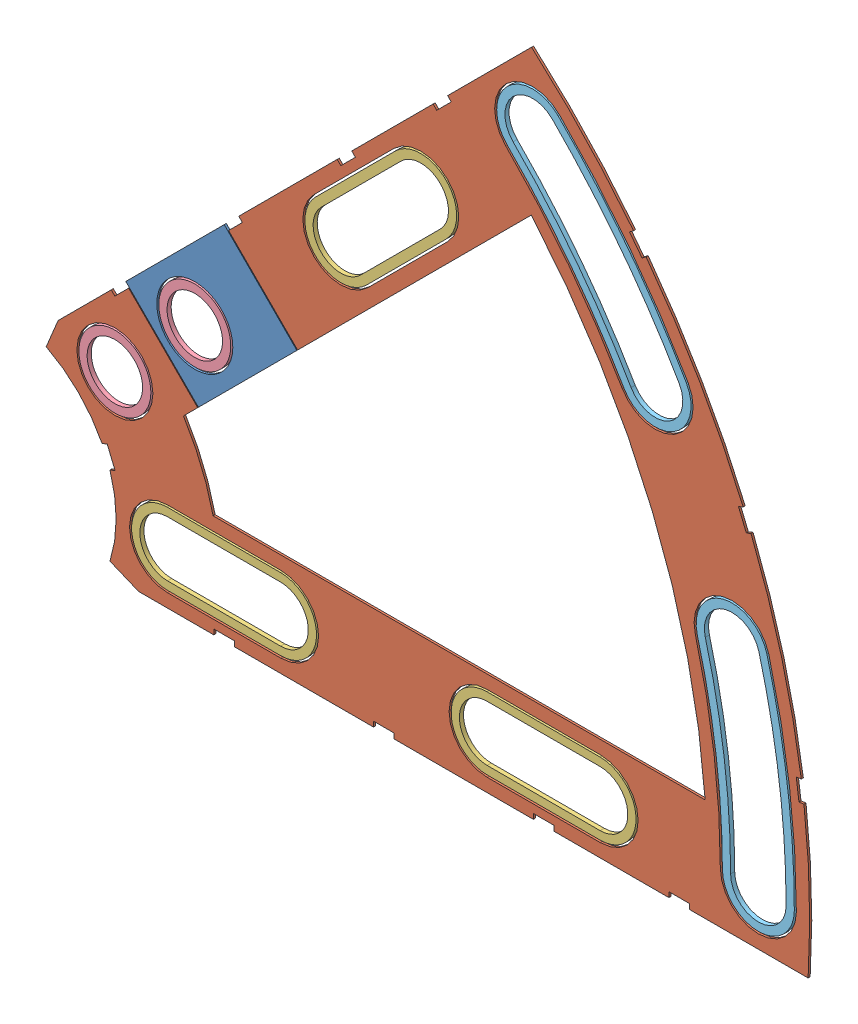
SolidWorks assembly Clover_2_Insul+Pass, configuration Default. Lengths in mm.
Overall size (94.37 82.54 0.51).
9 component instances, 5 part files, 22 mates.
Components (placement in the parent):
- Clover_2_Pass-1: Clover_2_Pass [Default] at (-7.6628 -2.4823 32.3476) size (21.15 21.15 0.25)
- Clover_2_Insul-1: Clover_2_Insul [Default] at (-7.6628 -2.4823 32.3476) size (94.37 82.54 0.25)
- Clover_Short_Washer-1: Clover_Short_Washer [Default] at (21.5472 -2.4823 32.6016) x (1 0 0) z (0 1 0) size (22.86 0.51 8.89)
- Clover_Short_Washer-2: Clover_Short_Washer [Default] at (61.0442 -2.4823 32.6016) x (1 0 0) z (0 1 0) size (22.86 0.51 8.89)
- Clover_Short_Washer-3: Clover_Short_Washer [Default] at (40.9204 46.1009 32.6016) x (0.707107 0.707107 0) z (-0.707107 0.707107 0) size (22.86 0.51 8.89)
- Round_Washer-1: Round_Washer [Default] at (8.0526 13.2332 32.6016) x (1 0 0) z (0 1 0) size (8.89 0.51 8.89)
- Round_Washer-2: Round_Washer [Default] at (17.9309 23.1115 32.6016) x (1 0 0) z (0 1 0) size (8.89 0.51 8.89)
- Clover_Outside_Washer-1: Clover_Outside_Washer [Default] at (-7.6628 -2.4823 32.0936) x (0.866025 0.5 0) z (0.5 -0.866025 0) size (12.14 0.51 33.54)
- Clover_Outside_Washer-2: Clover_Outside_Washer [Default] at (-7.6628 -2.4823 32.0936) x (1 0 0) z (0 -1 0) size (12.14 0.51 33.54)
Mates (geometry in assembly coordinates):
- Coincident1: coincident: plane of Clover_2_Pass-1 through (-7.6628 -2.4823 32.6016) normal (0 0 1); plane of Clover_2_Insul-1 through (-7.6628 -2.4823 32.6016) normal (0 0 1)
- Coincident3: coincident: plane of Clover_2_Pass-1 through (59.5487 73.7094 32.6016) normal (-0.707107 0.707107 0); plane of Clover_2_Insul-1 through (59.5487 73.7094 32.6016) normal (-0.707107 0.707107 0)
- Distance1: distance = 2.54 mm: plane of Clover_2_Pass-1 through (9.3997 23.5605 32.3476) normal (-0.707107 -0.707107 0); plane of Clover_2_Insul-1 through (7.6036 21.7644 32.3476) normal (0.707107 0.707107 0)
- Concentric1: concentric: circle of Clover_2_Insul-1; circle of Clover_Outside_Washer-1
- Concentric2: concentric: circle of Clover_2_Insul-1; circle of Clover_Outside_Washer-1
- Coincident4: coincident: plane of Clover_2_Insul-1 through (-7.6628 -2.4823 32.6016) normal (0 0 1); plane of Clover_Outside_Washer-1 through (33.5816 21.3302 32.6016) normal (0 0 1)
- Concentric3: concentric: circle of Clover_2_Insul-1; circle of Clover_Outside_Washer-2
- Concentric4: concentric: circle of Clover_2_Insul-1; circle of Clover_Outside_Washer-2
- Coincident5: coincident: plane of Clover_2_Insul-1 through (-7.6628 -2.4823 32.6016) normal (0 0 1); plane of Clover_Outside_Washer-2 through (39.9622 -2.4823 32.6016) normal (0 0 1)
- Concentric5: concentric: circle of Clover_2_Insul-1; circle of Clover_Short_Washer-2
- Concentric6: concentric: circle of Clover_2_Insul-1; circle of Clover_Short_Washer-2
- Coincident6: coincident: plane of Clover_2_Insul-1 through (-7.6628 -2.4823 32.6016) normal (0 0 1); plane of Clover_Short_Washer-2 through (54.0592 -2.4823 32.6016) normal (0 0 1)
- Concentric7: concentric: circle of Clover_2_Insul-1; circle of Clover_Short_Washer-1
- Concentric8: concentric: circle of Clover_2_Insul-1; circle of Clover_Short_Washer-1
- Coincident7: coincident: plane of Clover_2_Insul-1 through (-7.6628 -2.4823 32.6016) normal (0 0 1); plane of Clover_Short_Washer-1 through (14.5622 -2.4823 32.6016) normal (0 0 1)
- Concentric9: concentric: circle of Clover_2_Insul-1; circle of Clover_Short_Washer-3
- Concentric10: concentric: circle of Clover_2_Insul-1; circle of Clover_Short_Washer-3
- Coincident8: coincident: plane of Clover_2_Insul-1 through (-7.6628 -2.4823 32.6016) normal (0 0 1); plane of Clover_Short_Washer-3 through (35.9812 41.1618 32.6016) normal (0 0 1)
- Concentric11: concentric: circle of Clover_2_Pass-1; circle of Round_Washer-2
- Coincident9: coincident: plane of Clover_2_Pass-1 through (-7.6628 -2.4823 32.6016) normal (0 0 1); plane of Round_Washer-2 through (17.9309 23.1115 32.6016) normal (0 0 1)
- Concentric12: concentric: circle of Clover_2_Insul-1; circle of Round_Washer-1
- Coincident10: coincident: plane of Clover_2_Insul-1 through (-7.6628 -2.4823 32.6016) normal (0 0 1); plane of Round_Washer-1 through (8.0526 13.2332 32.6016) normal (0 0 1)
